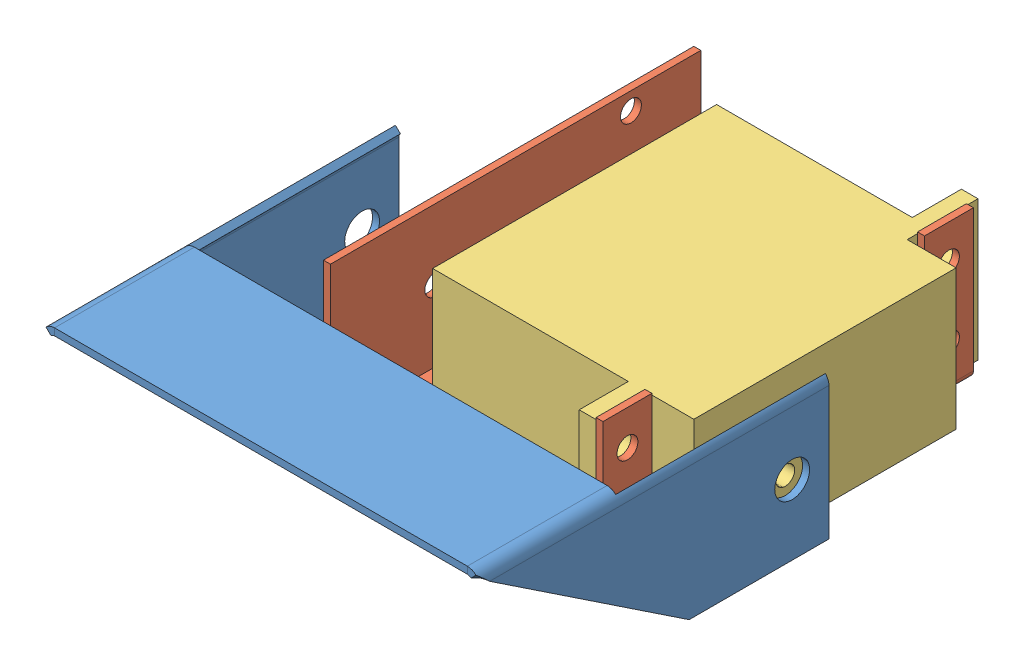
SolidWorks assembly FootAssembled, configuration Default. Lengths in mm.
Overall size (72.54 33.99 82.83).
3 component instances, 3 part files, 7 mates.
Components (placement in the parent):
- Foot-1: Foot [Default] at (8.4592 32.9907 36.861) x (-1 0 0) z (0 -1 0) size (62.54 50 20.77)
- Hub-1: Hub [Default] at (-0.2754 12.2253 8.6871) x (-1 0 0) z (0 0 -1) size (40 21.21 53)
- MotorHX5010-1: MotorHX5010 [Default] at (56.0859 33.2253 17.7657) x (0 -1 0) z (0 0 -1) size (20 40.87 54.68)
Mates (geometry in assembly coordinates):
- Distance1: distance = 15 mm: point of assembly; point of Hub-1
- Coincident13: coincident: plane of Hub-1 through (-0.2754 13.2253 8.6871) normal (0 1 0); plane of MotorHX5010-1 through (56.0859 13.2253 17.7657) normal (0 -1 0)
- Coincident14: coincident: plane of Hub-1 through (58.7246 33.4399 1.6871) normal (0 0 -1); line of MotorHX5010-1 through (58.7246 13.2253 1.6871) axis (0 1 0)
- Coincident15: coincident: plane of Hub-1 through (58.7246 -46.5601 8.6871) normal (-1 0 0); plane of MotorHX5010-1 through (58.7246 33.2253 17.7657) normal (1 0 0)
- Coincident17: coincident: line of Foot-1 through (47.4778 23.2253 -7.8829) axis (1 0 0); line of MotorHX5010-1 through (5.702 23.2253 -7.8829) axis (1 0 0)
- Coincident19: coincident: circle of Foot-1; circle of MotorHX5010-1
- LimitAngle1: limit planar angle = 0 rad: plane of Foot-1 through (8.4592 32.9907 36.861) normal (0 -1 0); plane of MotorHX5010-1 through (56.0859 33.2253 17.7657) normal (0 1 0)
